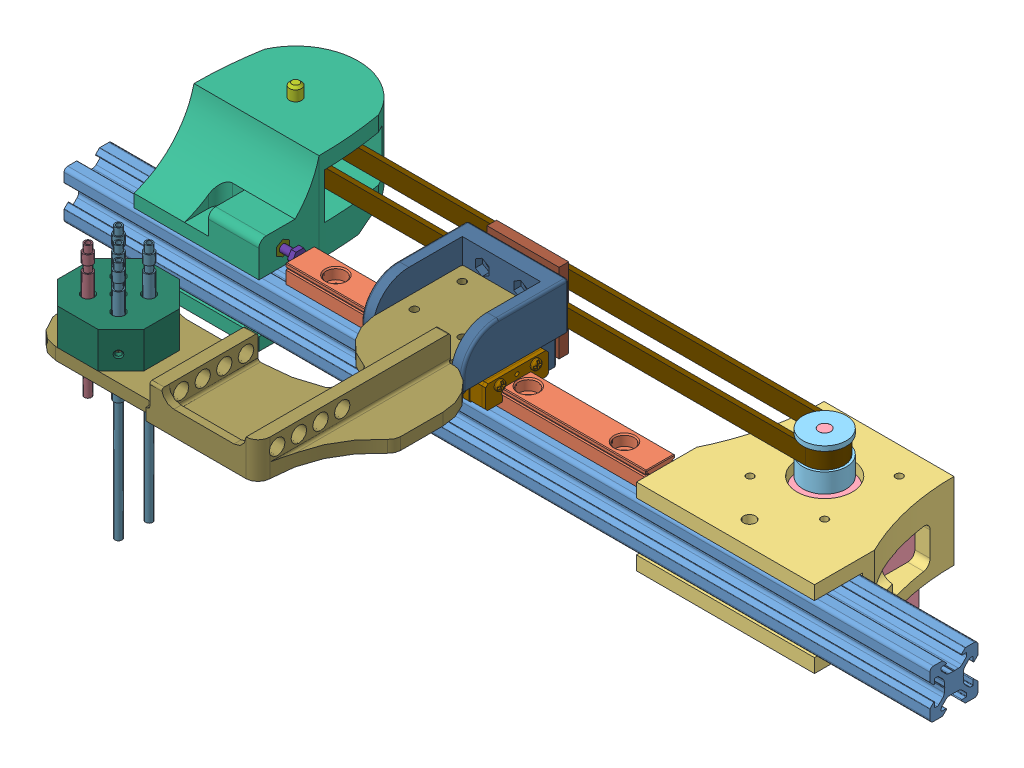
SolidWorks assembly Профиль с направляющей и паллетой, configuration По умолчанию. Lengths in mm.
Overall size (360 115.27 159).
25 component instances, 18 part files, 24 mates.
Components (placement in the parent):
- Вертикальный профиль 3-1: Вертикальный профиль 3 [00] at (0 10 -10) x (0 0 1) z (-1 0 0) size (20 20 360)
- Рельса малая-1: Рельса малая [По умолчанию] at (-122 28 -4) x (0 0 -1) z (0 1 0) size (12 150 8)
- Двигатель с креплением зеркально 2-1: Двигатель с креплением зеркально 2 [По умолчанию] at (-48 10 0) x (0 0 1) z (0 -1 0) size (68 74 63)
  - Крепление двигателя зеркально-1: Крепление двигателя зеркально [По умолчанию] at (0 37 -26) size (68 74 32)
  - Нема17-1: Нема17 [По умолчанию] at (-52.8678 35.3862 0.75) x (-1 0 0) z (0 0 -1) size (42.3 42.3 63)
  - Шкив-1: Шкив [По умолчанию] at (-41.25 37 -15.85) x (-1 0 0) z (0 -1 0) size (18 17.4 18)
- Ролик с креплением зеркально-1: Ролик с креплением зеркально [По умолчанию] at (-279 10 0) x (0 0 1) z (0 -1 0) size (93.13 52 97.57)
  - Крепление ролика зеркально-1: Крепление ролика зеркально [По умолчанию] at (0 26 -15.5) size (93.13 52 92.27)
  - Шпилька-1: Шпилька [По умолчанию] at (-41.25 26 -47.8005) size (5 5 40)
  - Ролик-1: Ролик [По умолчанию] at (-41.25 26 -32.05) x (1 0 0) z (0 -1 0) size (18 9 18)
- Ползун с зажимом зеркально-2: Ползун с зажимом зеркально [По умолчанию] at (-181.6854 33 -10) x (0 1 0) z (0 0 1) size (34 71.49 50.2)
  - Ползун-1: Ползун [Default] at (-13 6.5 0) x (0 0 1) z (0 1 0) size (27 10 50.47)
  - Тавр-1: Тавр [По умолчанию] at (4 6.7 -18) x (0 0 1) z (-1 0 0) size (44.2 66.29 34)
  - Прижимная планка 3-1: Прижимная планка 3 [По умолчанию] at (-0.7637 -0.7936 -44.6739) x (0 0 1) z (-1 0 0) size (4 30 33)
- Паллета с иглами-1: Паллета с иглами [По умолчанию] at (-188.3854 42 91) size (116.5 100 117)
  - Паллета-1: Паллета [По умолчанию] at (-32 -5 -30) size (116.5 17 117)
  - Игла без соска малая-1: Игла без соска малая [По умолчанию] at (-84.364 33.5 -13.636) x (-1 0 0) z (0 0 1) size (4 55 4)
  - Игла без соска большая 1-1: Игла без соска большая 1 [По умолчанию] at (-84.364 33.5 -26.364) x (1 0 0) z (0 0 -1) size (4 100 4)
  - Игла без соска большая 1-2: Игла без соска большая 1 [По умолчанию] at (-71.636 33.5 -13.636) x (-1 0 0) z (0 0 1) size (4 100 4)
  - Игла без соска большая 1-3: Игла без соска большая 1 [По умолчанию] at (-78 33.5 -20) x (-1 0 0) z (0 0 1) size (4 100 4)
  - колпачок-1: колпачок [По умолчанию] at (-78 0 -20) size (36 15 35)
  - Игла без соска большая 1-4: Игла без соска большая 1 [По умолчанию] at (-71.636 33.5 -26.364) x (1 0 0) z (0 0 -1) size (4 100 4)
- гайка H15M3-1: гайка H15M3 [По умолчанию] at (-279 26.75 -10) x (0 0.866025 -0.5) z (0 0.5 0.866025) size (5.5 15 6.35)
- болт М3-1: болт М3 [По умолчанию] at (-272 26.75 -10) x (0 -0.5 0.866025) z (0 -0.866025 -0.5) size (5.5 17 6.35)
- Лента малая в контексте^Профиль с направляющей и паллетой-1: Лента малая в контексте^Профиль с направляющей и паллетой [По умолчанию] at origin size (236.1 7.4 16.1) (virtual)
Mates (geometry in assembly coordinates):
- Совпадение1: coincident anti-aligned: plane of Вертикальный профиль 3-1 through (-360 0 -18.5) normal (0 -1 0); plane of assembly through (0 0 0) normal (0 1 0)
- Совпадение2: coincident aligned: plane of Вертикальный профиль 3-1 through (-360 1.5 0) normal (0 0 1); plane of assembly through (0 0 0) normal (0 0 1)
- Совпадение3: coincident aligned: plane of Вертикальный профиль 3-1 through (0 10.3377 -13.75) normal (1 0 0); plane of assembly through (0 0 0) normal (1 0 0)
- Совпадение5: coincident anti-aligned: plane of Вертикальный профиль 3-1 through (-360 20 -1.5) normal (0 1 0); plane of Рельса малая-1 through (-272 20 -4) normal (0 -1 0)
- Совпадение6: coincident aligned: plane of Вертикальный профиль 3-1; plane of Рельса малая-1
- Совпадение15: coincident aligned: plane of Вертикальный профиль 3-1; plane of Двигатель с креплением зеркально 2-1/Крепление двигателя зеркально-1
- Совпадение16: coincident anti-aligned: plane of Вертикальный профиль 3-1 through (-360 18.5 -20) normal (0 0 -1); plane of Двигатель с креплением зеркально 2-1/Крепление двигателя зеркально-1 through (-85 36 -20) normal (0 0 1)
- Совпадение17: coincident anti-aligned: plane of Рельса малая-1 through (-122 28 -4) normal (1 0 0); plane of Двигатель с креплением зеркально 2-1/Крепление двигателя зеркально-1 through (-122 -16 0) normal (-1 0 0)
- Совпадение18: coincident aligned: plane of Вертикальный профиль 3-1; plane of Ролик с креплением зеркально-1/Крепление ролика зеркально-1
- Совпадение19: coincident anti-aligned: plane of Вертикальный профиль 3-1 through (-360 5.17 -20) normal (0 0 -1); plane of Ролик с креплением зеркально-1/Крепление ролика зеркально-1 through (-305 25.5 -20) normal (0 0 1)
- Совпадение21: coincident aligned: plane of Вертикальный профиль 3-1; plane of Ползун с зажимом зеркально-2/Ползун-1 through (-188.1854 20 -10) normal (0 0 -1)
- Концентричный4: concentric aligned: cylinder of Рельса малая-1 through (-122 26 -16) axis (-1 0 0) radius 0.559; cylinder of Ползун с зажимом зеркально-2/Ползун-1 through (-183.1854 26 -16) axis (-1 0 0) radius 0.559
- Параллельность2: parallel anti-aligned: plane of Двигатель с креплением зеркально 2-1/Крепление двигателя зеркально-1 through (-122 -16 0) normal (-1 0 0); plane of Ползун с зажимом зеркально-2/Ползун-1 through (-181.6854 26 -4) normal (1 0 0)
- Концентричный7: concentric aligned: cylinder of Ползун с зажимом зеркально-2/Тавр-1 through (-194.3854 33 -20) axis (0 1 0) radius 1.6; cylinder of Паллета с иглами-1/Паллета-1 through (-194.3854 29 -20) axis (0 1 0) radius 1.6
- Концентричный8: concentric aligned: cylinder of Ползун с зажимом зеркально-2/Тавр-1 through (-214.3854 33 0) axis (0 1 0) radius 1.6; cylinder of Паллета с иглами-1/Паллета-1 through (-214.3854 29 0) axis (0 1 0) radius 1.6
- Совпадение23: coincident anti-aligned: plane of Ползун с зажимом зеркально-2/Тавр-1 through (-188.3854 37 -28) normal (0 1 0); plane of Паллета с иглами-1/Паллета-1 through (-220.3854 37 61) normal (0 -1 0)
- Совпадение24: coincident: plane of Рельса малая-1 through (-122 28 -4) normal (1 0 0); line of assembly
- Совпадение25: coincident anti-aligned: plane of Ролик с креплением зеркально-1/Крепление ролика зеркально-1 through (-294 28.3377 -12.75) normal (0 -0.866025 0.5); plane of гайка H15M3-1 through (-294 29.9254 -10) normal (0 0.866025 -0.5)
- Совпадение26: coincident anti-aligned: plane of Ролик с креплением зеркально-1/Крепление ролика зеркально-1 through (-294 29.9254 -10) normal (0 -0.866025 -0.5); plane of гайка H15M3-1 through (-294 28.3377 -7.25) normal (0 0.866025 0.5)
- Совпадение27: coincident anti-aligned: plane of Ролик с креплением зеркально-1/Крепление ролика зеркально-1 through (-294 25.5 0) normal (1 0 0); plane of гайка H15M3-1 through (-294 26.75 -10) normal (-1 0 0)
- Совпадение28: coincident anti-aligned: plane of гайка H15M3-1 through (-279 26.75 -10) normal (1 0 0); plane of болт М3-1
- Концентричный10: concentric aligned: cylinder of гайка H15M3-1 through (-294 26.75 -10) axis (1 0 0) radius 1.5; cylinder of болт М3-1 through (-289 26.75 -10) axis (1 0 0) radius 1.5
- Параллельность3: parallel aligned: plane of Ролик с креплением зеркально-1/Крепление ролика зеркально-1 through (-324.6388 34.64 0) normal (0 1 0); plane of болт М3-1 through (-274 29.5 -8.4123) normal (0 1 0)
- Совпадение30: coincident anti-aligned: plane of Рельса малая-1 through (-272 28 -4) normal (-1 0 0); plane of болт М3-1 through (-272 26.75 -10) normal (1 0 0)
